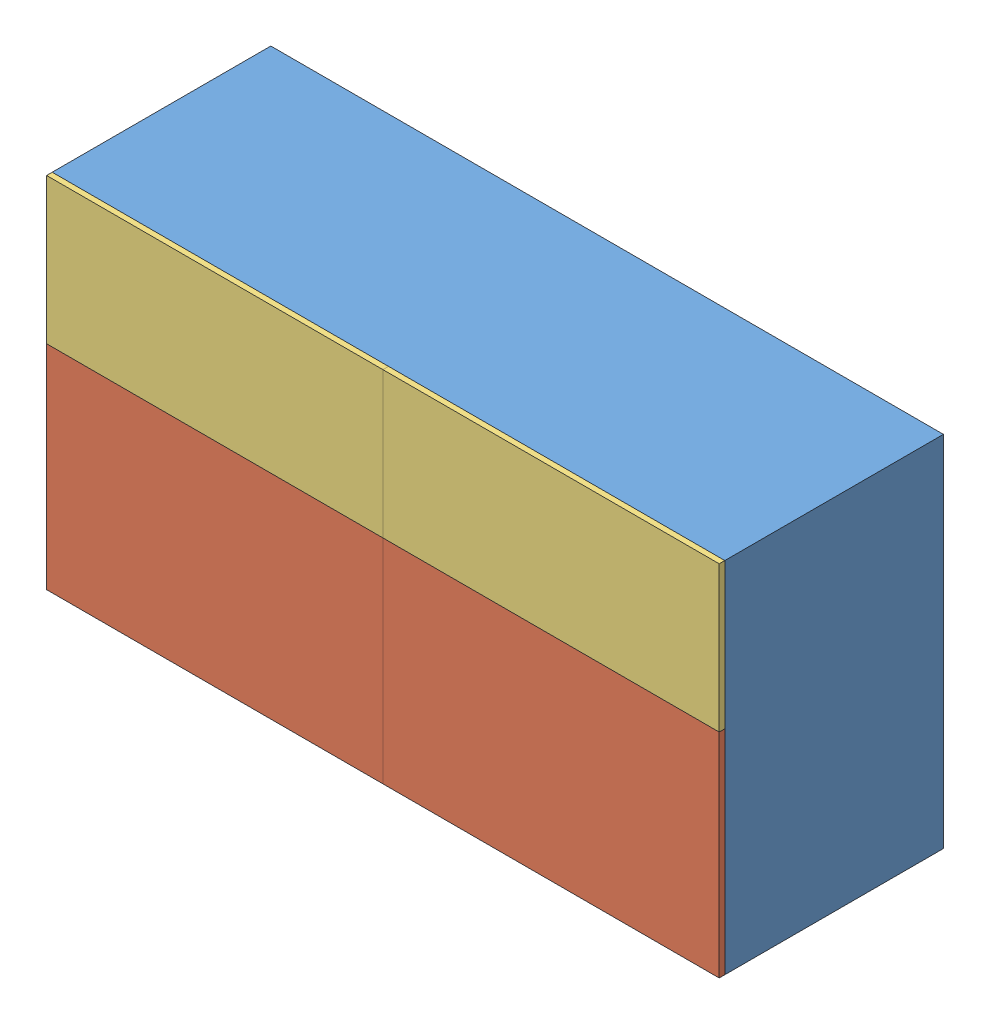
SolidWorks assembly Tv-Schubladen, configuration Standard. Lengths in mm.
Overall size (1200 640 400).
5 component instances, 3 part files, 18 mates.
Components (placement in the parent):
- TV-Korpus-1: TV-Korpus [Standard] at (-203.545 35.1714 1200) size (1200 640 390)
- Schublade-Hoch-1: Schublade-Hoch [Standard] at (96.455 -94.8286 1590) size (600 380 380)
- Schublade-Tief-1: Schublade-Tief [Standard] at (96.455 225.1714 1590) size (600 260 380)
- Schublade-Tief-3: Schublade-Tief [Standard] at (-503.545 225.1714 1590) size (600 260 380)
- Schublade-Hoch-3: Schublade-Hoch [Standard] at (-503.545 -94.8286 1590) size (600 380 380)
Mates (geometry in assembly coordinates):
- Deckungsgleich1: coincident anti-aligned: plane of TV-Korpus-1 through (-203.545 35.1714 1210) normal (0 0 1); plane of ? through (-503.545 -137.2651 1210) normal (0 0 -1)
- Deckungsgleich2: coincident anti-aligned: plane of TV-Korpus-1 through (-203.545 35.1714 1210) normal (0 0 1); plane of ? through (-503.545 10.0754 1210) normal (0 0 -1)
- Deckungsgleich3: coincident anti-aligned: plane of TV-Korpus-1 through (-203.545 35.1714 1210) normal (0 0 1); plane of ? through (-503.545 154.52 1210) normal (0 0 -1)
- Deckungsgleich7: coincident anti-aligned: plane of TV-Korpus-1 through (-783.545 -264.8286 1590) normal (0 1 0); plane of Schublade-Hoch-1 through (-183.545 -264.8286 1230) normal (0 -1 0)
- Deckungsgleich8: coincident anti-aligned: plane of TV-Korpus-1 through (-203.545 35.1714 1590) normal (0 0 1); plane of Schublade-Hoch-1 through (96.455 -94.8286 1590) normal (0 0 -1)
- Deckungsgleich10: coincident anti-aligned: plane of TV-Korpus-1 through (-203.545 35.1714 1590) normal (0 0 1); plane of Schublade-Tief-1 through (96.455 225.1714 1590) normal (0 0 -1)
- Deckungsgleich12: coincident anti-aligned: plane of Schublade-Hoch-1 through (-203.545 95.1714 1600) normal (0 1 0); plane of Schublade-Tief-1 through (-203.545 95.1714 1600) normal (0 -1 0)
- Deckungsgleich13: coincident anti-aligned: plane of TV-Korpus-1 through (-783.545 335.1714 1590) normal (1 0 0); plane of ? through (-783.545 159.52 1210) normal (-1 0 0)
- Deckungsgleich14: coincident anti-aligned: plane of TV-Korpus-1 through (-783.545 335.1714 1590) normal (1 0 0); plane of ? through (-783.545 15.0754 1210) normal (-1 0 0)
- Deckungsgleich15: coincident anti-aligned: plane of TV-Korpus-1 through (-783.545 335.1714 1590) normal (1 0 0); plane of ? through (-783.545 -132.2651 1210) normal (-1 0 0)
- Deckungsgleich16: coincident anti-aligned: plane of TV-Korpus-1 through (376.455 335.1714 1590) normal (-1 0 0); plane of Schublade-Tief-1 through (376.455 315.1714 1230) normal (1 0 0)
- Deckungsgleich17: coincident anti-aligned: plane of TV-Korpus-1 through (376.455 335.1714 1590) normal (-1 0 0); plane of Schublade-Hoch-1 through (376.455 -264.8286 1230) normal (1 0 0)
- Deckungsgleich19: coincident anti-aligned: plane of Schublade-Tief-3 through (-803.545 213.5076 1600) normal (0 -1 0); plane of Schublade-Hoch-3 through (-803.545 213.5076 1600) normal (0 1 0)
- Deckungsgleich20: coincident anti-aligned: plane of TV-Korpus-1 through (-203.545 35.1714 1590) normal (0 0 1); plane of Schublade-Tief-3 through (-503.545 225.1714 1590) normal (0 0 -1)
- Deckungsgleich21: coincident anti-aligned: plane of TV-Korpus-1 through (-203.545 35.1714 1590) normal (0 0 1); plane of Schublade-Hoch-3 through (-503.545 -94.8286 1590) normal (0 0 -1)
- Deckungsgleich22: coincident aligned: plane of TV-Korpus-1 through (-803.545 -284.8286 1210) normal (-1 0 0); plane of Schublade-Hoch-3 through (-803.545 -284.8286 1600) normal (-1 0 0)
- Deckungsgleich23: coincident aligned: plane of TV-Korpus-1 through (-803.545 -284.8286 1210) normal (-1 0 0); plane of Schublade-Tief-3 through (-803.545 95.1714 1600) normal (-1 0 0)
- Deckungsgleich24: coincident aligned: plane of TV-Korpus-1 through (-803.545 355.1714 1210) normal (0 1 0); plane of Schublade-Tief-3 through (-803.545 355.1714 1600) normal (0 1 0)
